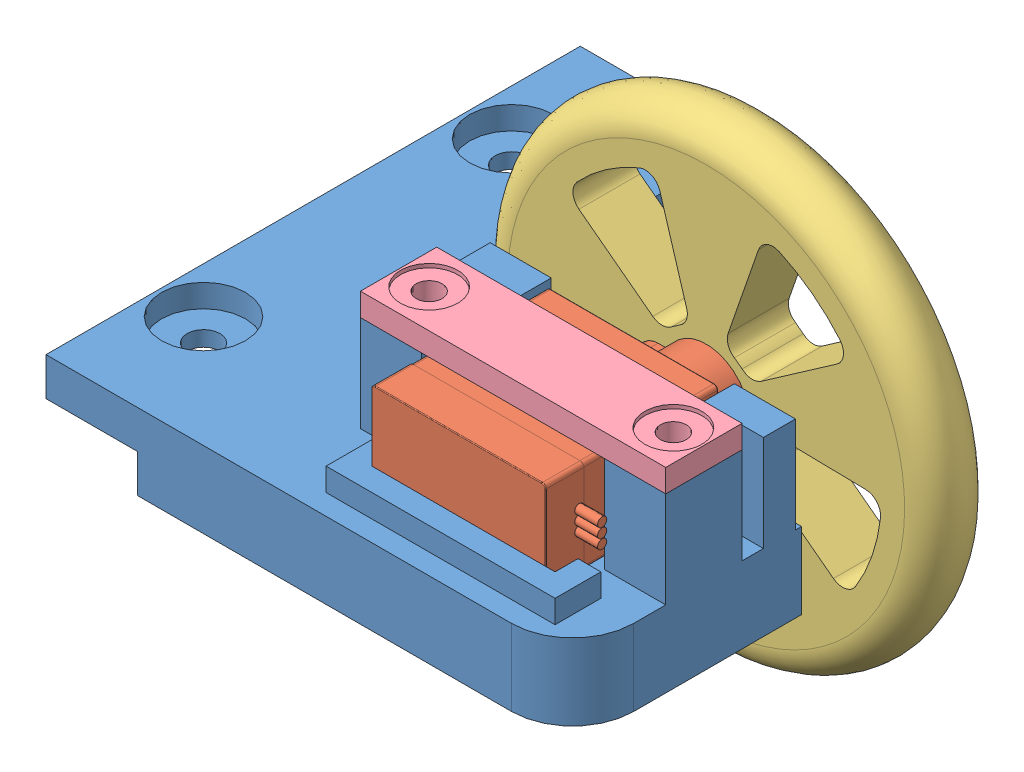
SolidWorks assembly D_V01, configuration Default. Lengths in mm.
Overall size (95.82 84.05 70.36).
4 component instances, 4 part files, 8 mates.
Components (placement in the parent):
- Structure BW_D_V01-1: Structure BW_D_V01 [Default] at (-26.8185 20.8348 0.7554) size (69 22.6 70.36)
- FS09R_Servo_Motor-1: FS09R_Servo_Motor [Varsayılan] at (-0.4685 26.9348 30.0554) x (0 1 0) z (-1 0 0) size (12.3 30 32.25)
- servo_wheel_D_V01-1: servo_wheel_D_V01 [Default] at (4.9815 26.9348 -0.9446) x (0 0 1) z (-0.797464 0.603366 0) size (8 60 60)
- Servo_fix_D_V01-1: Servo_fix_D_V01 [Default] at (-19.8185 36.4348 13.5554) size (40 3 10)
Mates (geometry in assembly coordinates):
- Coincident1: coincident: plane of Structure BW_D_V01-1 through (-26.8185 20.8348 0.7554) normal (0 1 0); plane of FS09R_Servo_Motor-1 through (-11.3185 20.8348 13.7054) normal (0 -1 0)
- Parallel2: parallel: line of Structure BW_D_V01-1 through (-48.8185 20.8348 35.7554) axis (1 0 0); line of FS09R_Servo_Motor-1 through (-11.3935 20.8848 30.0554) axis (1 0 0)
- Coincident4: coincident: plane of Structure BW_D_V01-1 through (-26.8185 23.8348 30.0554) normal (0 0 -1); plane of FS09R_Servo_Motor-1 through (-11.3935 21.2848 30.0554) normal (0 0 1)
- Coincident5: coincident: plane of Structure BW_D_V01-1 through (-11.8185 33.4348 0.7554) normal (1 0 0); plane of FS09R_Servo_Motor-1 through (-11.8185 21.3348 13.7054) normal (-1 0 0)
- Coincident6: coincident: circle of FS09R_Servo_Motor-1; plane of servo_wheel_D_V01-1 through (4.9815 26.9348 0.0554) normal (0 0 1)
- Concentric1: concentric: cylinder of FS09R_Servo_Motor-1 through (4.9815 26.9348 2.9554) axis (0 0 1) radius 5.65; circle of servo_wheel_D_V01-1
- Coincident7: coincident: plane of Structure BW_D_V01-1 through (-26.8185 33.4348 0.7554) normal (0 1 0); plane of Servo_fix_D_V01-1 through (-19.8185 33.4348 13.5554) normal (0 -1 0)
- Concentric3: concentric: cylinder of Structure BW_D_V01-1 through (-15.8185 27.4348 18.5554) axis (0 1 0) radius 1.5; cylinder of Servo_fix_D_V01-1 through (-15.8185 36.4348 18.5554) axis (0 1 0) radius 1.7
